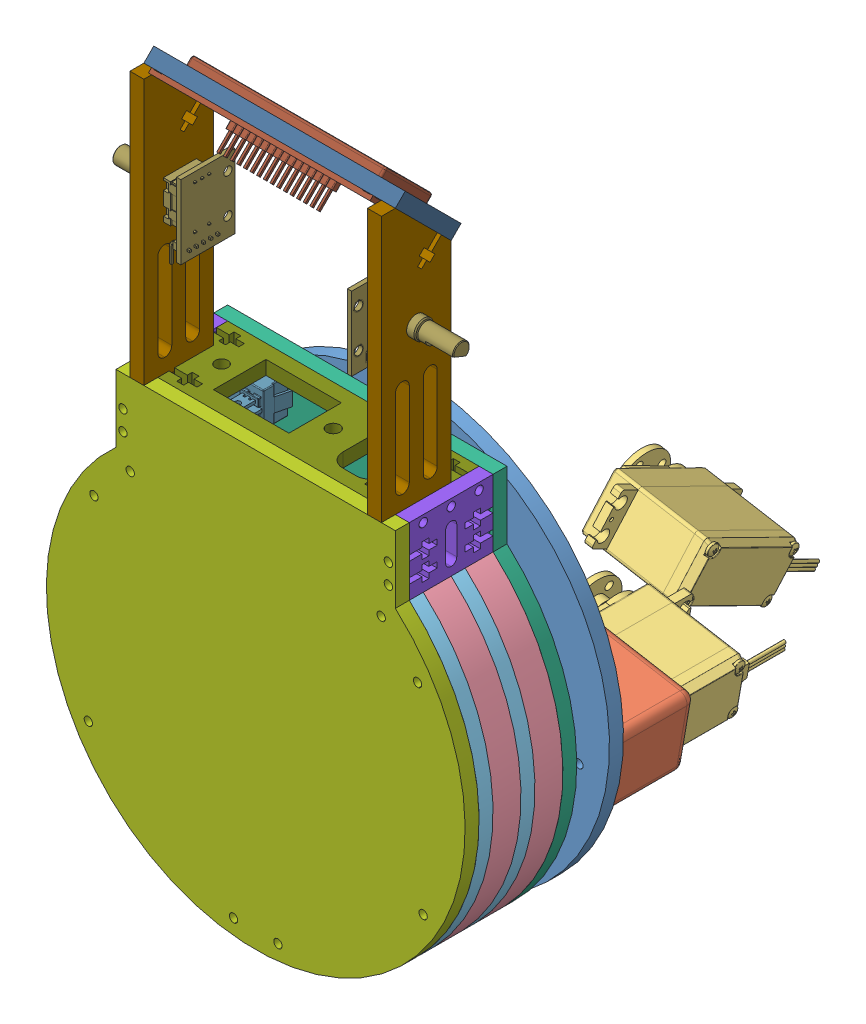
SolidWorks assembly Braço, configuration Valor predeterminado. Lengths in mm.
Overall size (173.5 269.68 214.3).
38 component instances, 25 part files, 68 mates.
Components (placement in the parent):
- base redonda-1: base redonda [Valor predeterminado] at (94.9745 195.5899 52.1477) x (0.171453 0.985192 0) z (0 0 1) size (150 150 5)
- Sup vertical-1: Sup vertical [Valor predeterminado] at (147.0611 180.8887 43.6477) x (0.171207 0.985235 0) z (0 0 -1) size (26.85 45.25 26.5)
- Servo-MG-995-4: Servo-MG-995 [Valor predeterminado] at (147.6509 190.4973 -49.8523) x (0.171207 0.985235 0) z (0 0 1) size (20 46.48 67)
- Sup vertical-2: Sup vertical [Valor predeterminado] at (42.888 210.2911 43.6477) x (-0.171207 -0.985235 0) z (0 0 -1) size (26.85 45.25 26.5)
- Servo-MG-995-5: Servo-MG-995 [Valor predeterminado] at (42.2982 200.6825 -49.8523) x (-0.171207 -0.985235 0) z (0 0 1) size (20 46.48 67)
- JuntaPrincpal-1: JuntaPrincpal [Valor predeterminado] at (-59.2954 177.0362 -25.8279) x (-0.150063 -0.863559 0.481401) z (0.985235 -0.171207 0) size (41.02 127.72 47.2) (hidden)
  - TT DIREITA-1: TT DIREITA [Valor predeterminado] at (-20.4895 -55.6066 125.2156) size (41.02 127.72 5)
  - H1-1: H1 [Valor predeterminado] at (-20.4895 -55.6066 130.2156) size (7.02 75.61 37.2)
  - H2-1: H2 [Valor predeterminado] at (-20.4895 -55.6066 130.2156) size (6.85 69.87 37.2)
  - TT ESQUERDA-1: TT ESQUERDA [Valor predeterminado] at (-20.4895 -55.6066 167.4156) size (41.02 127.72 5)
- Servo-MG-995-6: Servo-MG-995 [Valor predeterminado] at (76.4778 124.9495 -127.3334) x (0.150063 0.863561 -0.481398) z (0.082419 0.47429 0.876502) size (20 46.48 67)
- JuntaSecundaria]-1: JuntaSecundaria] [Valor predeterminado] at (136.5941 115.5994 -35.1236) x (0.111812 0.643437 0.75729) z (-0.985235 0.171207 0) size (75.57 157.19 70) (hidden)
  - PSL esquerda-1: PSL esquerda [Valor predeterminado] at (-10.1158 -52.8118 30) size (5.52 44.7 60)
  - PS DIREITA-2: PS DIREITA [Valor predeterminado] at (-10.1158 -52.8118 90) size (40 90 5)
  - PS ESQUERDA-1: PS ESQUERDA [Valor predeterminado] at (-10.1158 -52.8118 25) size (40 90 5)
  - PSL esquerda-2: PSL esquerda [Valor predeterminado] at (-10.1158 -52.8118 90) x (-1 0 0) z (0 0 -1) size (5.52 44.7 60)
  - SuporteServoGarra-1: SuporteServoGarra [Valor predeterminado] at (-16.2216 -30.0963 51.7505) x (0 0 1) z (0 1 0) size (70 27.14 5)
  - Servo-MG-995-1: Servo-MG-995 [Valor predeterminado] at (-14.1523 -20.4258 -5.5896) x (-1 0 0) z (0 0 1) size (20 46.48 67)
  - SuporteGarra-1: SuporteGarra [Valor predeterminado] at (-4.9505 -77.565 60.0715) x (-0.881873 0 -0.471488) z (-0.471488 0 0.881873) size (75 42.69 20)
- Servo-MG-995-7: Servo-MG-995 [Valor predeterminado] at (32.0745 191.5527 86.3182) x (-0.000003 -1 0) z (1 -0.000003 0) size (20 46.48 67)
- Parte impressa base-1: Parte impressa base [Valor predeterminado] at (100.4791 419.9221 73.8477) size (150 130.9 10)
- Parte acrilico base-1: Parte acrilico base [Valor predeterminado] at (100.4791 419.9221 83.8477) size (150 130.9 5)
- Parte impressa base-2: Parte impressa base [Valor predeterminado] at (100.4791 419.9221 88.8477) size (150 130.9 10)
- Parte acrilico base-2: Parte acrilico base [Valor predeterminado] at (100.4791 419.9221 98.8477) size (150 130.9 5)
- Cima base-1: Cima base [Valor predeterminado] at (100.4795 419.9221 68.8477) size (150 155 5)
- Baixo base-1: Baixo base [Valor predeterminado] at (100.4791 419.9221 103.8477) size (150 155 5)
- Lateral Base-1: Lateral Base [Valor predeterminado] at (44.9058 272.0165 119.3072) x (0 1 0) z (1 0 0) size (24.1 30 5)
- Lateral lcd-1: Lateral lcd [Valor predeterminado] at (49.9058 325.8776 95.8831) x (0 -1 0) z (1 0 0) size (100 25 5)
- Lateral lcd-2: Lateral lcd [Valor predeterminado] at (134.9745 325.8776 95.8831) x (0 -1 0) z (1 0 0) size (100 25 5)
- FrenteLCD-1: FrenteLCD [Valor predeterminado] at (75.1267 362.1989 88.3857) x (1 0 0) z (0 -0.707107 0.707107) size (90.06 28.28 5)
- LCDScreen-1: LCDScreen [Default] at (94.6608 359.4349 94.9378) x (1 0 0) z (0 0.707107 0.707107) size (79.38 18.26 34.92)
- Lateral Base-3: Lateral Base [Valor predeterminado] at (139.9745 272.0165 119.3072) x (0 1 0) z (1 0 0) size (24.1 30 5)
- rotary encoder_chesr_2013-1: rotary encoder_chesr_2013 [Valor predeterminado] at (68.4018 307.4987 65.9451) x (0 -1 0) z (-1 0 0) size (30.28 19.33 30.07)
- rotary encoder_chesr_2013-2: rotary encoder_chesr_2013 [Valor predeterminado] at (121.8595 307.4987 126.7503) x (0 -1 0) z (1 0 0) size (30.28 19.33 30.07)
- PCB-1: PCB [Valor predeterminado] at (131.5276 260.2378 100.8477) x (0 -1 0) z (0 0 1) size (100 80 3)
- Switch-1: Switch [Valor predeterminado] at (62.6561 263.1899 68.8477) x (1 0 0) z (0 1 0) size (21.54 28.83 15)
- Ballcaster-1: Ballcaster [Valor predeterminado] at (95.5159 243.0235 68.8477) x (-0.923728 -0.383049 0) z (0 0 -1) size (18.98 12 10.26)
- FrenteBase-1: FrenteBase [Valor predeterminado] at (81.6336 270.5899 82.2607) x (1 0 0) z (0 1 0) size (90.07 30 5)
Mates (geometry in assembly coordinates):
- Coincidente128: coincident anti-aligned: plane of base redonda-1 through (94.9745 195.5899 52.1477) normal (0 0 -1); plane of Sup vertical-1 through (147.0611 180.8887 52.1477) normal (0 0 1)
- Concêntrico28: concentric anti-aligned: circle of base redonda-1; circle of Sup vertical-1
- Concêntrico29: concentric anti-aligned: circle of base redonda-1; circle of Sup vertical-1
- Coincidente131: coincident anti-aligned: plane of Sup vertical-1 through (162.2398 173.8158 25.6477) normal (0.171207 0.985235 0); plane of Servo-MG-995-4 through (135.737 178.4213 3.0477) normal (-0.171207 -0.985235 0)
- Coincidente132: coincident anti-aligned: plane of Sup vertical-1 through (162.2398 173.8158 25.6477) normal (-0.985235 0.171207 0); plane of Servo-MG-995-4 through (163.9348 183.5697 23.3477) normal (0.985235 -0.171207 0)
- Coincidente133: coincident anti-aligned: plane of Sup vertical-1 through (147.0611 180.8887 43.6477) normal (0 0 -1); plane of Servo-MG-995-4 through (135.737 178.4213 43.6477) normal (0 0 1)
- Coincidente134: coincident anti-aligned: plane of Sup vertical-2 through (27.7092 217.3639 25.6477) normal (-0.171207 -0.985235 0); plane of Servo-MG-995-5 through (54.2121 212.7584 3.0477) normal (0.171207 0.985235 0)
- Coincidente135: coincident anti-aligned: plane of Sup vertical-2 through (27.7092 217.3639 25.6477) normal (0.985235 -0.171207 0); plane of Servo-MG-995-5 through (26.0143 207.6101 23.3477) normal (-0.985235 0.171207 0)
- Coincidente136: coincident anti-aligned: plane of Sup vertical-2 through (42.888 210.2911 43.6477) normal (0 0 -1); plane of Servo-MG-995-5 through (54.2121 212.7584 43.6477) normal (0 0 1)
- Coincidente137: coincident aligned: circle of base redonda-1; circle of Sup vertical-2
- Concêntrico30: concentric anti-aligned: circle of base redonda-1; circle of Sup vertical-2
- Coincidente168: coincident anti-aligned: plane of Servo-MG-995-5 through (71.7292 199.6661 13.0477) normal (0.985235 -0.171207 0); plane of JuntaPrincpal-1/TT DIREITA-1 through (71.7292 199.6661 13.0477) normal (-0.985235 0.171207 0)
- Concêntrico43: concentric anti-aligned: circle of Servo-MG-995-5; circle of JuntaPrincpal-1/TT DIREITA-1
- Concêntrico49: concentric aligned: circle of JuntaPrincpal-1/TT DIREITA-1; circle of Servo-MG-995-6
- Concêntrico50: concentric aligned: circle of JuntaPrincpal-1/TT DIREITA-1; circle of Servo-MG-995-6
- Coincidente172: coincident anti-aligned: plane of JuntaPrincpal-1/TT DIREITA-1 through (76.6554 198.81 13.0477) normal (0.985235 -0.171207 0); plane of Servo-MG-995-6 through (66.033 137.6822 -80.874) normal (-0.985235 0.171207 0)
- Concêntrico51: concentric aligned: circle of Servo-MG-995-6; circle of JuntaSecundaria]-1/PS DIREITA-2
- Coincidente173: coincident anti-aligned: plane of Servo-MG-995-6 through (52.3163 156.29 -70.2579) normal (-0.985235 0.171207 0); plane of JuntaSecundaria]-1/PS DIREITA-2 through (39.9446 85.0958 -8.2939) normal (0.985235 -0.171207 0)
- Coincidente181: coincident anti-aligned: plane of Parte impressa base-1 through (94.9745 195.5899 73.8477) normal (0 0 -1); plane of Cima base-1 through (94.9749 195.5899 73.8477) normal (0 0 1)
- Concêntrico52: concentric aligned: circle of Parte impressa base-1; circle of Cima base-1
- Coincidente183: coincident anti-aligned: plane of Parte impressa base-1 through (94.9745 195.5899 83.8477) normal (0 0 1); plane of Parte acrilico base-1 through (100.4791 419.9221 83.8477) normal (0 0 -1)
- Coincidente187: coincident aligned: circle of Parte impressa base-1; circle of Parte acrilico base-1
- Coincidente188: coincident anti-aligned: plane of Parte acrilico base-1 through (100.4791 419.9221 88.8477) normal (0 0 1); plane of Parte impressa base-2 through (94.9745 195.5899 88.8477) normal (0 0 -1)
- Coincidente189: coincident aligned: circle of Parte acrilico base-1; circle of Parte impressa base-2
- Coincidente190: coincident anti-aligned: plane of Parte impressa base-2 through (94.9745 195.5899 98.8477) normal (0 0 1); plane of Parte acrilico base-2 through (100.4791 419.9221 98.8477) normal (0 0 -1)
- Coincidente191: coincident aligned: circle of Parte impressa base-2; circle of Parte acrilico base-2
- Coincidente193: coincident anti-aligned: plane of Parte acrilico base-2 through (100.4791 419.9221 103.8477) normal (0 0 1); plane of Baixo base-1 through (94.9745 195.5899 103.8477) normal (0 0 -1)
- Coincidente194: coincident aligned: circle of Parte acrilico base-2; circle of Baixo base-1
- Coincidente195: coincident anti-aligned: plane of Baixo base-1 through (94.9745 195.5899 103.8477) normal (0 0 -1); plane of Lateral Base-1 through (49.9058 251.4916 103.8477) normal (0 0 1)
- Coincidente196: coincident anti-aligned: plane of Parte impressa base-1 through (67.0237 251.4916 83.8477) normal (0 1 0); plane of Lateral Base-1 through (49.9058 251.4916 103.8477) normal (0 -1 0)
- Coincidente197: coincident aligned: plane of Baixo base-1 through (44.9058 251.529 108.8477) normal (-1 0 0); plane of Lateral Base-1 through (44.9058 272.0165 119.3072) normal (-1 0 0)
- Coincidente202: coincident anti-aligned: plane of Lateral Base-1 through (49.9058 272.0165 119.3072) normal (1 0 0); plane of Lateral lcd-1 through (49.9058 325.8776 95.8831) normal (-1 0 0)
- Coincidente203: coincident anti-aligned: plane of Baixo base-1 through (94.9745 195.5899 103.8477) normal (0 0 -1); plane of Lateral lcd-1 through (54.9058 370.5899 103.8477) normal (0 0 1)
- Distância1: distance = 5 mm: plane of Baixo base-1 through (44.9058 275.5899 108.8477) normal (0 1 0); line of Lateral lcd-1 through (49.9058 270.5899 103.8477) axis (0 0 -1)
- Coincidente207: coincident anti-aligned: plane of Baixo base-1 through (94.9745 195.5899 103.8477) normal (0 0 -1); plane of Lateral lcd-2 through (139.9745 370.5899 103.8477) normal (0 0 1)
- Coincidente208: coincident: plane of Baixo base-1 through (44.9058 275.5899 108.8477) normal (0 1 0); moEndPointRef_w of Lateral lcd-2
- Coincidente209: coincident anti-aligned: plane of Lateral lcd-1 through (54.9058 370.5899 103.8477) normal (0 0.707107 -0.707107); plane of FrenteLCD-1 through (75.1267 358.6634 91.9212) normal (0 -0.707107 0.707107)
- Coincidente210: coincident: line of Lateral lcd-1 through (49.9058 350.5899 83.8477) axis (0 0.707107 0.707107); plane of FrenteLCD-1 through (49.9058 370.5869 103.8447) normal (-1 0 0)
- Coincidente213: coincident anti-aligned: line of Lateral lcd-1 through (54.9058 350.5899 83.8477) axis (-1 0 0); line of FrenteLCD-1 through (49.9058 350.5899 83.8477) axis (1 0 0)
- Coincidente214: coincident anti-aligned: plane of FrenteLCD-1 through (75.1267 358.6634 91.9212) normal (0 -0.707107 0.707107); plane of LCDScreen-1 through (94.6608 360.5574 93.8153) normal (0 0.707107 -0.707107)
- Coincidente215: coincident anti-aligned: plane of FrenteLCD-1 through (129.5858 352.1384 85.3963) normal (0 0.707107 0.707107); plane of LCDScreen-1 through (94.6608 357.7511 79.7836) normal (0 -0.707107 -0.707107)
- Coincidente216: coincident: line of FrenteLCD-1 through (129.5858 372.5738 98.7606) axis (0 -0.707107 -0.707107); plane of LCDScreen-1 through (129.5858 366.1701 88.2026) normal (1 0 0)
- Coincidente217: coincident anti-aligned: plane of Baixo base-1 through (94.9745 195.5899 103.8477) normal (0 0 -1); plane of Lateral Base-3 through (144.9745 251.4916 103.8477) normal (0 0 1)
- Coincidente219: coincident anti-aligned: plane of Parte impressa base-2 through (144.9745 251.4916 98.8477) normal (0 1 0); plane of Lateral Base-3 through (144.9745 251.4916 103.8477) normal (0 -1 0)
- Coincidente221: coincident aligned: plane of Baixo base-1 through (144.9745 251.4916 108.8477) normal (1 0 0); plane of Lateral Base-3 through (144.9745 272.0165 119.3072) normal (1 0 0)
- Concêntrico53: concentric aligned: circle of Lateral lcd-2; circle of rotary encoder_chesr_2013-1
- Coincidente222: coincident anti-aligned: plane of Lateral lcd-1 through (54.9058 325.8776 95.8831) normal (1 0 0); plane of rotary encoder_chesr_2013-1 through (54.9058 330.5899 96.3477) normal (-1 0 0)
- Concêntrico58: concentric anti-aligned: circle of Servo-MG-995-7; circle of Cima base-1
- Concêntrico59: concentric anti-aligned: circle of Servo-MG-995-7; circle of Cima base-1
- Concêntrico60: concentric anti-aligned: circle of base redonda-1; circle of Servo-MG-995-7
- Coincidente231: coincident anti-aligned: plane of Servo-MG-995-7 through (132.5746 204.4898 73.8477) normal (0 0 -1); plane of Cima base-1 through (94.9749 195.5899 73.8477) normal (0 0 1)
- Coincidente232: coincident anti-aligned: plane of base redonda-1 through (94.9745 195.5899 57.1477) normal (0 0 1); plane of Servo-MG-995-7 through (94.9745 195.5899 57.1477) normal (0 0 -1)
- Coincidente233: coincident anti-aligned: plane of Lateral lcd-2 through (139.9745 325.8776 95.8831) normal (1 0 0); plane of Lateral Base-3 through (139.9745 272.0165 119.3072) normal (-1 0 0)
- Paralelo4: parallel aligned: plane of Lateral lcd-1 through (54.9058 350.5899 83.8477) normal (0 0 -1); plane of rotary encoder_chesr_2013-1 through (63.3132 341.2059 84.6891) normal (0 0 -1)
- Concêntrico61: concentric anti-aligned: circle of Lateral lcd-2; circle of rotary encoder_chesr_2013-2
- Coincidente235: coincident anti-aligned: plane of Lateral lcd-2 through (134.9745 325.8776 95.8831) normal (-1 0 0); plane of rotary encoder_chesr_2013-2 through (134.9745 330.0819 96.3477) normal (1 0 0)
- Paralelo5: parallel aligned: plane of Lateral lcd-2 through (139.9745 350.5899 83.8477) normal (0 0 -1); plane of rotary encoder_chesr_2013-2 through (126.9481 314.7899 88.6769) normal (0 0 -1)
- Paralelo6: parallel anti-aligned: plane of Lateral lcd-2 through (139.9745 370.5899 108.8477) normal (0 1 0); plane of PCB-1 through (134.7671 165.5899 103.8477) normal (0 -1 0)
- Coincidente238: coincident anti-aligned: plane of Baixo base-1 through (94.9745 195.5899 103.8477) normal (0 0 -1); plane of PCB-1 through (131.5276 260.2378 103.8477) normal (0 0 1)
- Distância2: distance = 10 mm aligned: plane of PCB-1 through (134.7671 265.5899 103.8477) normal (0 1 0); plane of Baixo base-1 through (44.9058 275.5899 108.8477) normal (0 1 0)
- Coincidente242: coincident anti-aligned: plane of Cima base-1 through (71.4061 269.5899 68.8477) normal (0 -1 0); plane of Switch-1 through (53.4061 269.5899 83.0477) normal (0 1 0)
- Coincidente243: coincident anti-aligned: plane of Cima base-1 through (53.9061 256.7899 68.8477) normal (1 0 0); plane of Switch-1 through (53.9061 256.6899 68.8477) normal (-1 0 0)
- Coincidente244: coincident anti-aligned: plane of Cima base-1 through (94.9749 195.5899 68.8477) normal (0 0 -1); plane of Switch-1 through (72.1561 269.6899 68.8477) normal (0 0 1)
- Coincidente246: coincident anti-aligned: plane of Cima base-1 through (94.9749 195.5899 68.8477) normal (0 0 -1); plane of Ballcaster-1 through (95.4873 243.0116 68.8477) normal (0 0 1)
- Concêntrico62: concentric aligned: circle of Cima base-1; circle of Ballcaster-1
- Coincidente247: coincident anti-aligned: plane of Cima base-1 through (94.9749 195.5899 73.8477) normal (0 0 1); plane of FrenteBase-1 through (49.9058 275.5899 73.8477) normal (0 0 -1)
- Coincidente248: coincident aligned: plane of Cima base-1 through (44.9061 275.5899 73.8477) normal (0 1 0); plane of FrenteBase-1 through (81.6336 275.5899 82.2607) normal (0 1 0)
- Coincidente249: coincident anti-aligned: plane of Lateral lcd-1 through (54.9058 325.8776 95.8831) normal (1 0 0); plane of FrenteBase-1 through (54.9058 275.5899 103.8477) normal (-1 0 0)
